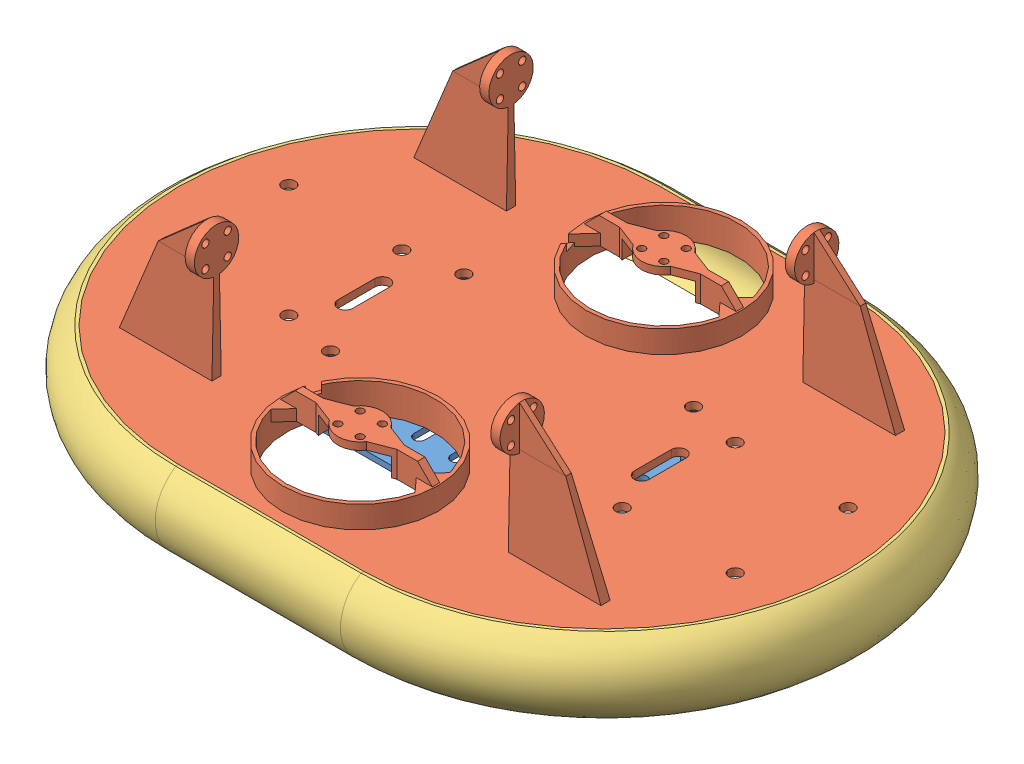
SolidWorks assembly Assem1, configuration Default. Lengths in mm.
Overall size (192.69 56 142.69).
3 component instances, 3 part files, 5 mates.
Components (placement in the parent):
- Battery_Holder-1: Battery_Holder [Default] at (28.556 30.7352 48.1837) size (67 15.5 41)
- Main_body-1: Main_body [Default] at (28.556 44.7352 48.1837) size (180 38 130)
- Skirt-1: Skirt [Default] at (28.556 38.6954 113.1837) size (192.69 20 142.69)
Mates (geometry in assembly coordinates):
- Coincident1: coincident anti-aligned: plane of Main_body-1 through (3.556 44.7352 48.1837) normal (0 -1 0); plane of Skirt-1 through (3.556 44.7352 -16.8163) normal (0 1 0)
- Concentric1: concentric aligned: circle of Main_body-1; circle of Skirt-1
- Concentric2: concentric anti-aligned: cylinder of Battery_Holder-1 through (-2.444 44.7352 66.1837) axis (0 -1 0) radius 1.5; cylinder of Main_body-1 through (-2.444 44.7342 66.1837) axis (0 1 0) radius 1.75
- Concentric3: concentric anti-aligned: cylinder of Battery_Holder-1 through (59.556 44.7352 30.1837) axis (0 -1 0) radius 1.5; cylinder of Main_body-1 through (59.556 44.7342 30.1837) axis (0 1 0) radius 1.75
- Coincident2: coincident anti-aligned: plane of Battery_Holder-1 through (59.556 44.7352 30.1837) normal (0 1 0); plane of Main_body-1 through (3.556 44.7352 48.1837) normal (0 -1 0)
